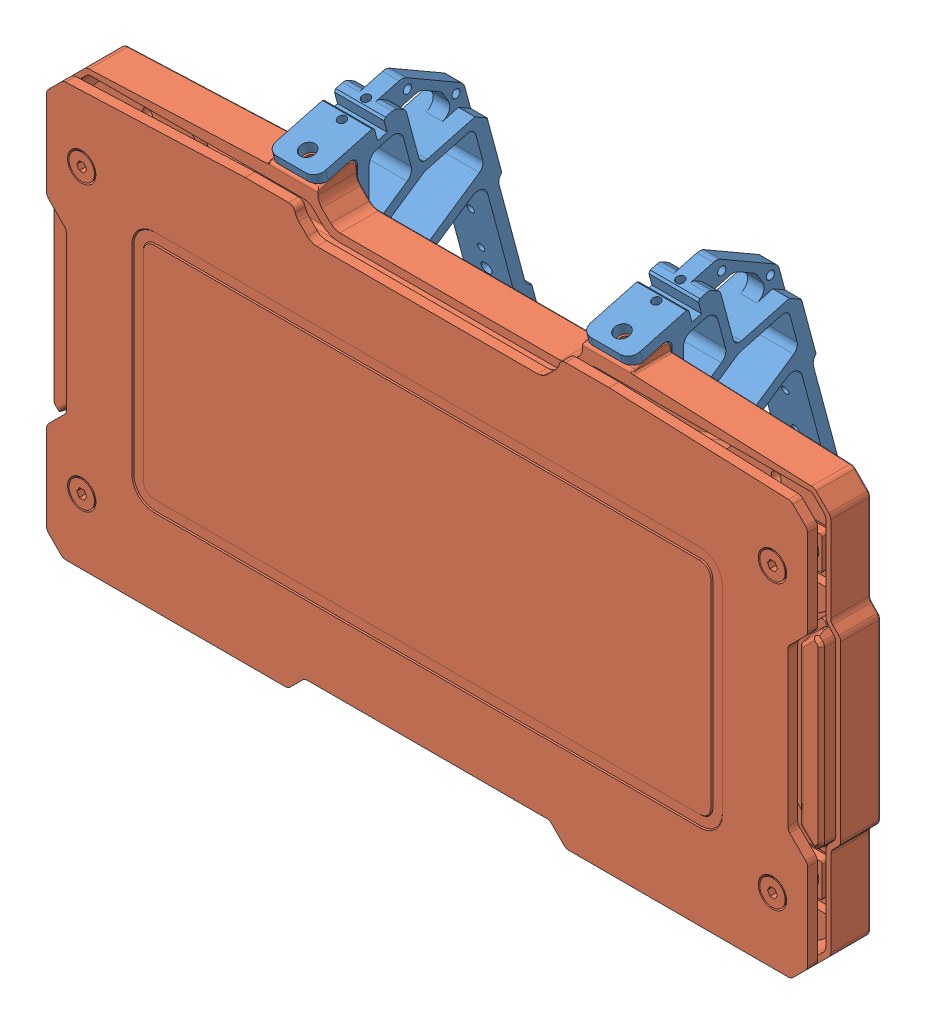
SolidWorks assembly 大装甲, configuration 默认. Lengths in mm.
Overall size (1209.52 987.78 836.1).
3 component instances, 2 part files, 15 mates.
Components (placement in the parent):
- RM2019裁判系统支撑架AH02-1: RM2019裁判系统支撑架AH02 [默认] at (-45.6645 -48.283 152.6103) size (15 130.97 68.39)
- RM2019裁判系统支撑架AH02-2: RM2019裁判系统支撑架AH02 [默认] at (49.3355 -48.283 152.6103) size (15 130.97 68.39)
- RM2019裁判系统装甲模块AM12-1: RM2019裁判系统装甲模块AM12 [默认] at (46.8398 150.7553 49.099) x (0 0.866025 0.5) z (1 0 0) size (874.78 460.39 1209.52)
Mates (geometry in assembly coordinates):
- 重合1: coincident anti-aligned: plane of RM2019裁判系统支撑架AH02-1 through (-3.4824 44.8918 152.6103) normal (0 0.965926 0.258819); plane of ? through (-53.1645 50.7171 130.8702) normal (0 -0.965926 -0.258819)
- 同心1: concentric aligned: cylinder of RM2019裁判系统支撑架AH02-1 through (-45.6645 39.8055 148.2611) axis (0 0.965926 0.258819) radius 1.25; cylinder of ? through (-45.6645 38.8769 148.0122) axis (0 0.965926 0.258819) radius 1.5
- 同心2: concentric aligned: cylinder of RM2019裁判系统支撑架AH02-1 through (-45.6645 40.7325 140.7449) axis (0 0.965926 0.258819) radius 1.25; cylinder of ? through (-45.6645 40.8181 140.7678) axis (0 0.965926 0.258819) radius 1.5
- 重合4: coincident anti-aligned: plane of RM2019裁判系统支撑架AH02-2 through (91.5176 44.8918 152.6103) normal (0 0.965926 0.258819); plane of ? through (41.8355 50.7171 130.8702) normal (0 -0.965926 -0.258819)
- 同心5: concentric aligned: cylinder of RM2019裁判系统支撑架AH02-2 through (49.3355 39.8055 148.2611) axis (0 0.965926 0.258819) radius 1.25; cylinder of ? through (49.3355 38.8769 148.0122) axis (0 0.965926 0.258819) radius 1.5
- 同心6: concentric aligned: cylinder of RM2019裁判系统支撑架AH02-2 through (49.3355 40.7325 140.7449) axis (0 0.965926 0.258819) radius 1.25; cylinder of ? through (49.3355 40.8181 140.7678) axis (0 0.965926 0.258819) radius 1.5
- 同心7: concentric: cylinder of ? through (-45.6645 57.3423 148.0942) axis (0 0.258819 -0.965926) radius 2.25; cylinder of ? through (-45.6645 59.9305 138.435) axis (0 -0.258819 0.965926) radius 1.65
- 重合5: coincident: plane of ? through (-24.0453 53.1691 136.6232) normal (0 0.258819 -0.965926); plane of ? through (-38.1645 53.1541 136.6192) normal (0 -0.258819 0.965926)
- 平行1: parallel: plane of ? through (-53.1645 53.1 136.7428) normal (0 0.866025 0.5); plane of ? through (1.8355 87.5118 77.11) normal (0 -0.866025 -0.5)
- 同心8: concentric: cylinder of ? through (49.3355 59.9305 138.435) axis (0 -0.258819 0.965926) radius 1.65; cylinder of ? through (49.3355 57.3423 148.0942) axis (0 0.258819 -0.965926) radius 2.25
- 重合6: coincident: plane of ? through (-38.1645 53.1541 136.6192) normal (0 -0.258819 0.965926); plane of ? through (70.9547 53.1691 136.6232) normal (0 0.258819 -0.965926)
- 平行2: parallel: plane of ? through (1.8355 87.5118 77.11) normal (0 -0.866025 -0.5); plane of ? through (41.8355 53.1 136.7428) normal (0 0.866025 0.5)
- 重合8: coincident anti-aligned: plane of RM2019裁判系统支撑架AH02-2 through (27.7162 41.5789 152.6103) normal (0 -0.965926 -0.258819); plane of RM2019裁判系统装甲模块AM12-1 through (41.8355 41.5809 152.6031) normal (0 0.965926 0.258819)
- 同心9: concentric anti-aligned: cylinder of RM2019裁判系统支撑架AH02-2 through (49.3355 49.4244 161.9676) axis (0 -0.965926 -0.258819) radius 2.25; cylinder of RM2019裁判系统装甲模块AM12-1 through (49.3355 39.7651 159.3794) axis (0 0.965926 0.258819) radius 1.65
- 同心10: concentric anti-aligned: cylinder of RM2019裁判系统支撑架AH02-1 through (-45.6645 49.4244 161.9676) axis (0 -0.965926 -0.258819) radius 2.25; cylinder of RM2019裁判系统装甲模块AM12-1 through (-45.6645 39.7651 159.3794) axis (0 0.965926 0.258819) radius 1.65
